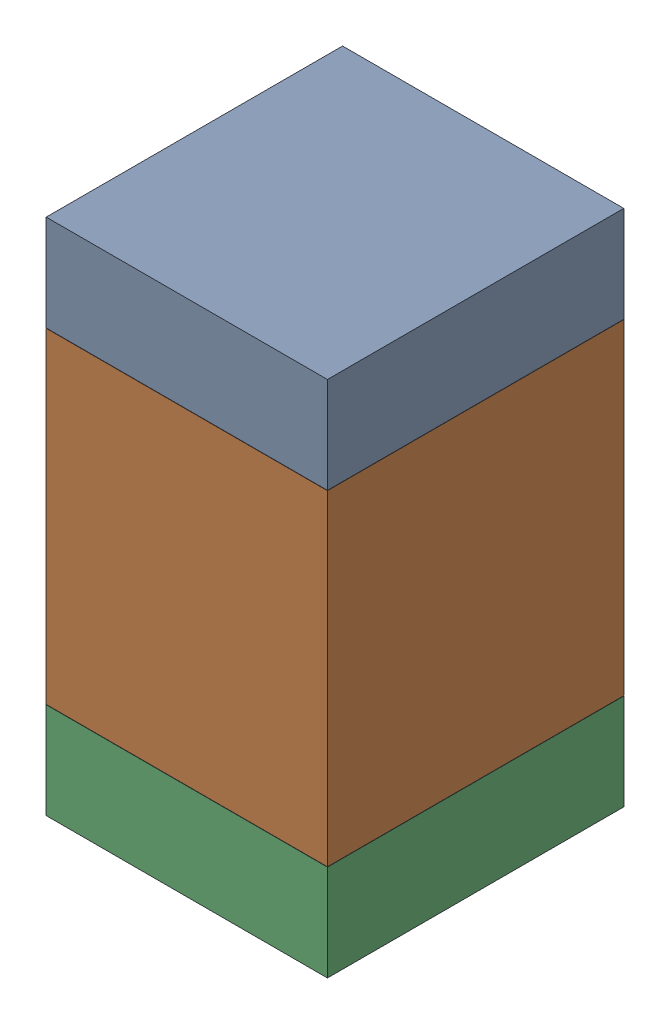
SolidWorks assembly R20, configuration Default. Lengths in mm.
Overall size (0.95 1.75 1).
6 component instances, 2 part files, 0 mates.
Components (placement in the parent):
- 6575495072-1: 6575495072 [Default] at (11.049 15.8255 0) size (0.95 0.32 1)
  - Extruded_6-1: Extruded_6 [Default] at origin size (0.95 0.32 1)
- 6575494912-1: 6575494912 [Default] at (11.049 15.113 0) size (0.95 1.1 1)
  - Extruded_7-1: Extruded_7 [Default] at origin size (0.95 1.1 1)
- 6575495072-2: 6575495072 [Default] at (11.049 14.4005 0) size (0.95 0.32 1)
  - Extruded_6-1: Extruded_6 [Default] at origin size (0.95 0.32 1)
